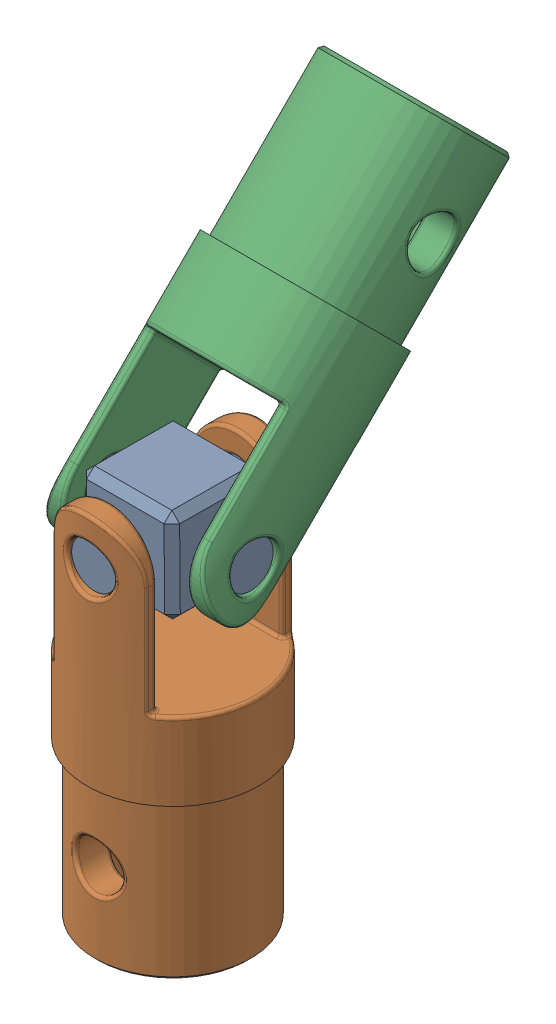
SolidWorks assembly Universal Coupling, configuration Default. Lengths in mm.
Overall size (11.13 41.49 25.55).
3 component instances, 2 part files, 6 mates.
Components (placement in the parent):
- Part2-1: Part2 [Default] at (-0.0246 889.1306 1267.8963) x (0.999932 0.008216 0.008216) z (0.008217 0 -0.999966) size (10 6 10)
- Part1-1: Part1 [Default] at (0 874.1307 1267.8966) x (-0.999966 0 -0.008217) z (0 1 0) size (11 11 25)
- Part1-2: Part1 [Default] at (0 894.616 1259.4113) x (0.01162 -0.707059 -0.707059) z (0 -0.707107 0.707107) size (11 11 25)
Mates (geometry in assembly coordinates):
- Concentric1: concentric anti-aligned: cylinder of Part2-1 through (-0.0411 886.1307 1272.8964) axis (0.008217 0 -0.999966) radius 1.45; cylinder of Part1-1 through (0.0452 886.1307 1262.3967) axis (-0.008217 0 0.999966) radius 1.5
- Concentric2: concentric aligned: cylinder of Part2-1 through (-4.9997 886.0896 1267.8555) axis (0.999932 0.008216 0.008216) radius 1.45; cylinder of Part1-2 through (-5.4996 886.0855 1267.8514) axis (0.999932 0.008216 0.008216) radius 1.5
- Distance1: distance = 1 mm anti-aligned: plane of Part2-1 through (-2.9505 883.1062 1264.8722) normal (0.008217 0 -0.999966); plane of Part1-1 through (5.5327 899.1857 1263.9419) normal (-0.008217 0 0.999966)
- Distance2: distance = 1 mm anti-aligned: plane of Part2-1 through (-2.9505 883.1062 1264.8722) normal (-0.999932 -0.008216 -0.008216); plane of Part1-2 through (-4.0636 880.7554 1280.9838) normal (0.999932 0.008216 0.008216)
- Concentric3: concentric aligned: cylinder of Part1-2 through (0 901.6871 1252.3402) axis (0 -0.707107 0.707107) radius 3
- Concentric4: concentric aligned: cylinder of Part1-1 through (0 864.1307 1267.8966) axis (0 1 0) radius 3
